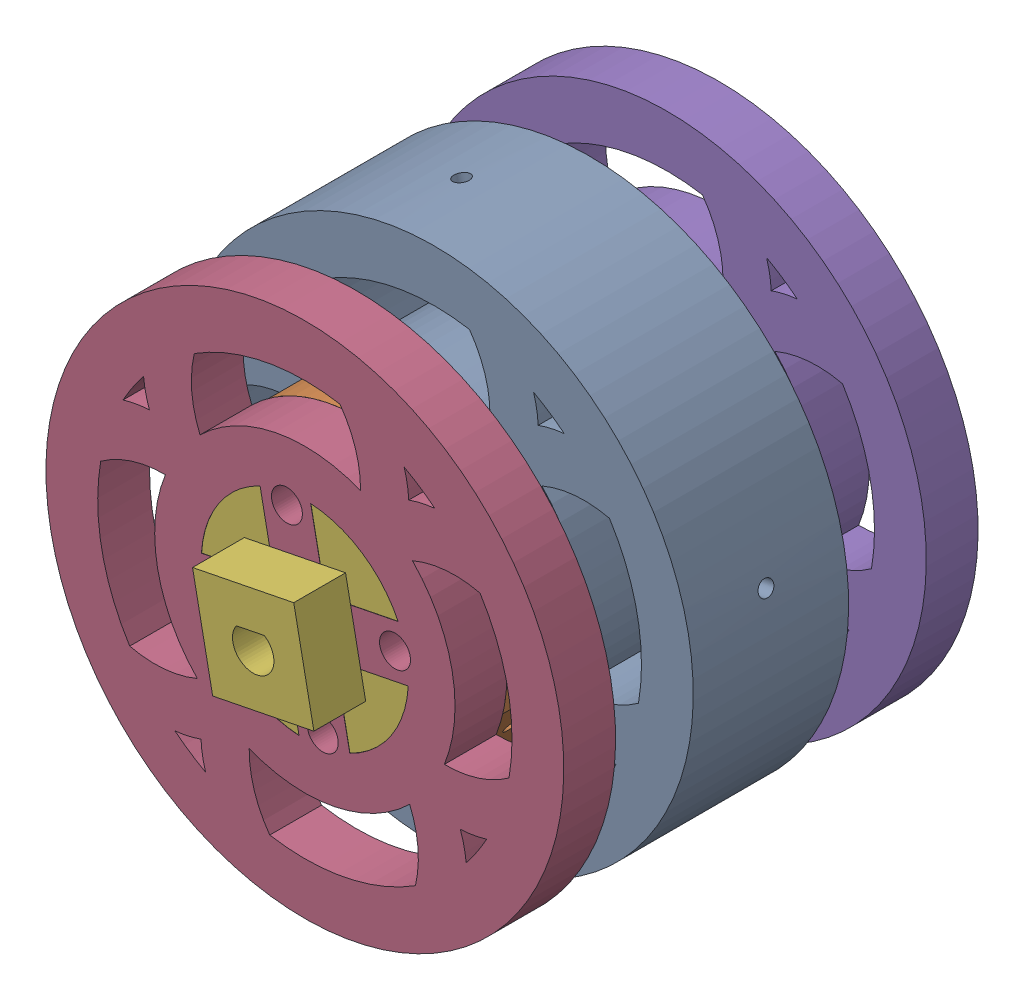
SolidWorks assembly Wheel_Assembly_With_Connector, configuration Default. Lengths in mm.
Overall size (117.59 117.59 90).
6 component instances, 4 part files, 17 mates.
Components (placement in the parent):
- Inner Ring Design-1: Inner Ring Design [Default] at (2.0234 14.792 3.8828) x (0.980785 0.19509 0) z (0 0 1) size (100 100 30)
- Motor_Connector_Ring-1: Motor_Connector_Ring [Default] at (2.0234 14.792 18.8828) x (0.980785 0.19509 0) z (0 0 1) size (58 58 15)
- Motor_Connector_Ring-2: Motor_Connector_Ring [Default] at (2.0234 14.792 -26.1172) x (0.980785 0.19509 0) z (0 0 1) size (58 58 15)
- Outer Ring Design-1: Outer Ring Design [Default] at (2.0234 14.792 28.8828) x (0.980785 0.19509 0) z (0 0 1) size (100 100 10)
- Outer Ring Design-2: Outer Ring Design [Default] at (2.0234 14.792 -41.1172) x (0.980785 0.19509 0) z (0 0 1) size (100 100 10)
- Wheel_Brushing_Connector-1: Wheel_Brushing_Connector [Default] at (2.0509 14.8333 -51.1172) x (0 0 1) z (-0.980785 -0.19509 0) size (90 38.73 38.73)
Mates (geometry in assembly coordinates):
- Distance1: distance = 25 mm aligned: plane of Inner Ring Design-1 through (2.0234 14.792 3.8828) normal (0 0 1); plane of Wheel Design-1 through (2.0234 14.792 28.8828) normal (0 0 1)
- Concentric3: concentric anti-aligned: cylinder of Wheel Design-1 through (2.0234 14.792 95.8828) axis (0 0 -1) radius 55; cylinder of Inner Ring Design-1 through (2.0234 14.792 -26.1172) axis (0 0 1) radius 50
- Parallel5: parallel aligned: cylinder of Wheel Design-1 through (-105.863 -6.6679 -11.1172) axis (0.980785 0.19509 0) radius 1.5; cylinder of Inner Ring Design-1 through (34.3893 21.23 -11.1172) axis (0.980785 0.19509 0) radius 1.5
- Coincident5: coincident anti-aligned: plane of Inner Ring Design-1 through (2.0234 14.792 3.8828) normal (0 0 1); plane of Motor_Connector_Ring-1 through (2.0234 14.792 3.8828) normal (0 0 -1)
- Concentric5: concentric anti-aligned: cylinder of Inner Ring Design-1 through (-1.4395 32.201 30.8828) axis (0 0 -1) radius 2.987; cylinder of Motor_Connector_Ring-1 through (-1.4395 32.201 -51.1172) axis (0 0 1) radius 3.15
- Coincident6: coincident aligned: plane of Inner Ring Design-1 through (11.8312 16.7429 -26.1172) normal (-0.980785 -0.19509 0); plane of Motor_Connector_Ring-1 through (11.8312 16.7429 3.8828) normal (-0.980785 -0.19509 0)
- Coincident7: coincident anti-aligned: plane of Inner Ring Design-1 through (2.0234 14.792 -26.1172) normal (0 0 -1); plane of Motor_Connector_Ring-2 through (2.0234 14.792 -26.1172) normal (0 0 1)
- Concentric6: concentric anti-aligned: cylinder of Inner Ring Design-1 through (19.4323 18.2549 30.8828) axis (0 0 -1) radius 2.987; cylinder of Motor_Connector_Ring-2 through (19.4323 18.2549 -96.1172) axis (0 0 1) radius 3.15
- Coincident8: coincident aligned: plane of Inner Ring Design-1 through (11.8312 16.7429 -26.1172) normal (-0.980785 -0.19509 0); plane of Motor_Connector_Ring-2 through (11.8312 16.7429 -41.1172) normal (-0.980785 -0.19509 0)
- Coincident9: coincident anti-aligned: plane of Motor_Connector_Ring-1 through (2.0234 14.792 18.8828) normal (0 0 1); plane of Outer Ring Design-1 through (2.0234 14.792 18.8828) normal (0 0 -1)
- Concentric7: concentric aligned: cylinder of Motor_Connector_Ring-1 through (19.4323 18.2549 -51.1172) axis (0 0 1) radius 3.15; cylinder of Outer Ring Design-1 through (19.4323 18.2549 18.8828) axis (0 0 1) radius 2.987
- Coincident10: coincident aligned: plane of Motor_Connector_Ring-1 through (11.8312 16.7429 3.8828) normal (-0.980785 -0.19509 0); plane of Outer Ring Design-1 through (11.8312 16.7429 18.8828) normal (-0.980785 -0.19509 0)
- Coincident12: coincident anti-aligned: plane of Motor_Connector_Ring-2 through (2.0234 14.792 -41.1172) normal (0 0 -1); plane of Outer Ring Design-2 through (2.0234 14.792 -41.1172) normal (0 0 1)
- Concentric8: concentric aligned: cylinder of Motor_Connector_Ring-2 through (-1.4395 32.201 -96.1172) axis (0 0 1) radius 3.15; cylinder of Outer Ring Design-2 through (-1.4395 32.201 -51.1172) axis (0 0 1) radius 2.987
- Coincident13: coincident aligned: plane of Motor_Connector_Ring-2 through (11.8312 16.7429 -41.1172) normal (-0.980785 -0.19509 0); plane of Outer Ring Design-2 through (11.8312 16.7429 -51.1172) normal (-0.980785 -0.19509 0)
- Coincident16: coincident anti-aligned: plane of Outer Ring Design-2 through (0.0725 24.5999 -51.1172) normal (0.19509 -0.980785 0); plane of Wheel_Brushing_Connector-1 through (0.1069 24.6067 38.8828) normal (-0.19509 0.980785 0)
- Coincident17: coincident aligned: plane of Outer Ring Design-2 through (2.0234 14.792 -51.1172) normal (0 0 -1); plane of Wheel_Brushing_Connector-1 through (2.0509 14.8333 -51.1172) normal (0 0 -1)
